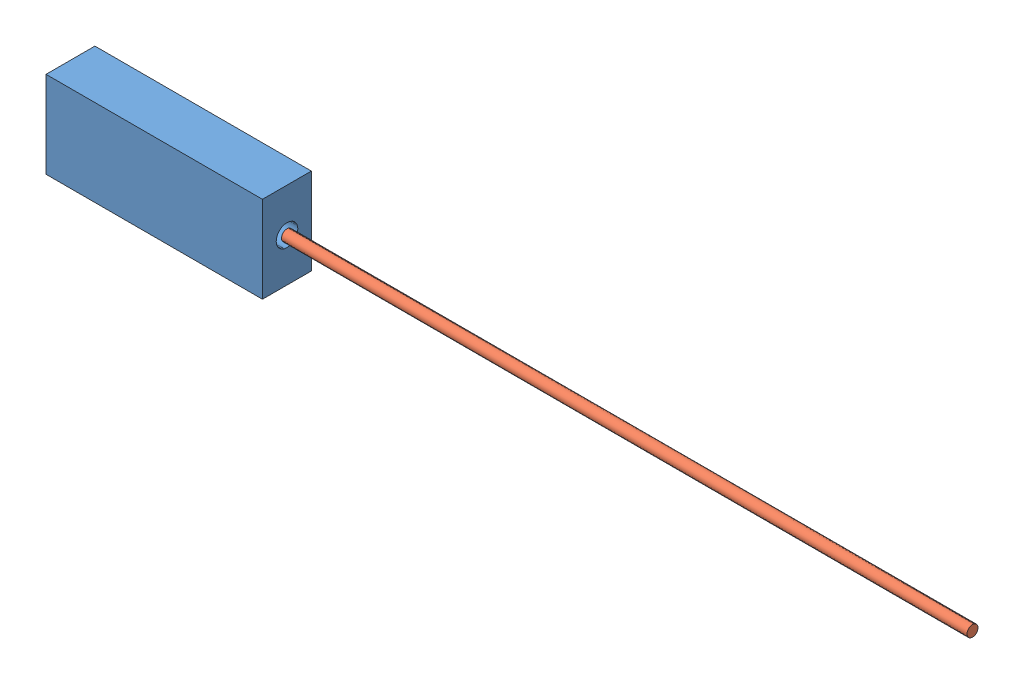
SolidWorks assembly Harness_27-CABLE_REALOP_ONE_ASSEMBLY, configuration AnnotateFlattenedRoute1 - Default. Lengths in mm.
Overall size (41.67 4 2.26).
3 component instances, 3 part files, 1 mates.
Components (placement in the parent):
- 1_PIN-1: 1_PIN [Default] at (-10 2 -1.125) x (0 0 1) z (1 0 0) size (2.26 4 20)
- Cable^Harness_27-CABLE_REALOP_ONE_ASSEMBLY-1: Cable^Harness_27-CABLE_REALOP_ONE_ASSEMBLY [Default] at origin size (12.6 26.11 29.22) (suppressed, hidden, virtual)
- Flattened_Cable^Harness_27-CABLE_REALOP_ONE_ASSEMBLY-1: Flattened_Cable^Harness_27-CABLE_REALOP_ONE_ASSEMBLY [Default] at origin (virtual)
Mates (geometry in assembly coordinates):
- Coincident1021: coincident anti-aligned: plane of X_AND_Y_SOLAR_ARRAYS-2 through (89.5177 -21.2025 126.3251) normal (-1 0 0); plane of 1_PIN-1 through (89.5177 42.1072 258.4563) normal (1 0 0)
